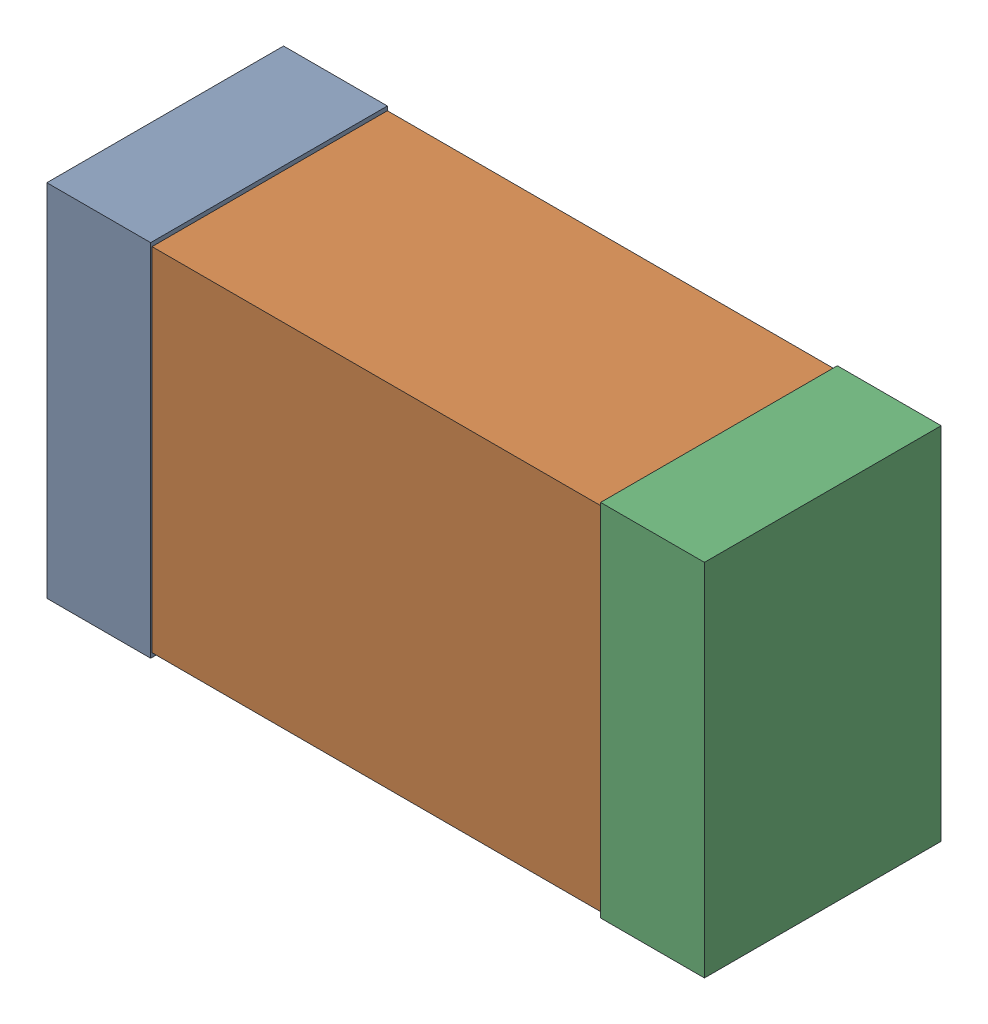
SolidWorks assembly R3Kanaloa_v2.0.0_Motor, configuration Default. Lengths in mm.
Overall size (2.38 1.3 0.85).
6 component instances, 2 part files, 0 mates.
Components (placement in the parent):
- 352877648-1: 352877648 [Default] at (41.656 65.024 0) size (0.38 1.3 0.85)
  - Extruded_14-1: Extruded_14 [Default] at origin size (0.38 1.3 0.85)
- 352877392-1: 352877392 [Default] at (42.656 65.024 0) size (2.2 1.27 0.85)
  - Extruded_15-1: Extruded_15 [Default] at origin size (2.2 1.27 0.85)
- 352877648-2: 352877648 [Default] at (43.656 65.024 0) size (0.38 1.3 0.85)
  - Extruded_14-1: Extruded_14 [Default] at origin size (0.38 1.3 0.85)
